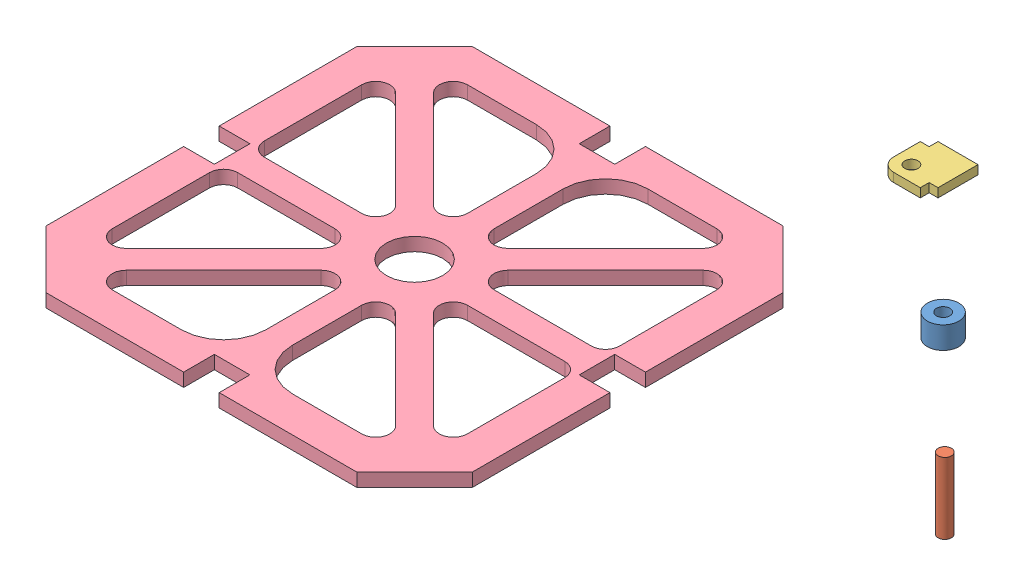
SolidWorks assembly Assem1, configuration Default. Lengths in mm.
Overall size (159.79 16 130.91).
4 component instances, 4 part files, 3 mates.
Components (placement in the parent):
- spacer-1: spacer [Default] at (56.4505 -16.1749 -20.7949) size (7.07 5 7.07)
- rod-1: rod [Default] at (94.9329 -16.1749 17.3147) size (3 16 3)
- board over hang clips-1: board over hang clips [Default] at (22.2397 -16.1749 -50.5387) size (11 2 11)
- Part3-1: Part3 [Default] at (-15.3583 -16.1749 26.4337) size (96 3 96)
Mates (geometry in assembly coordinates):
- Coincident1: coincident aligned: plane of rod-1 through (94.9329 -16.1749 17.3147) normal (0 -1 0); plane of Part3-1 through (-15.3583 -16.1749 26.4337) normal (0 -1 0)
- Coincident2: coincident aligned: plane of board over hang clips-1 through (20.6174 -16.1749 -48.4776) normal (0 -1 0); plane of Part3-1 through (-15.3583 -16.1749 26.4337) normal (0 -1 0)
- Coincident3: coincident aligned: plane of spacer-1 through (56.4505 -16.1749 -20.7949) normal (0 -1 0); plane of Part3-1 through (-15.3583 -16.1749 26.4337) normal (0 -1 0)
